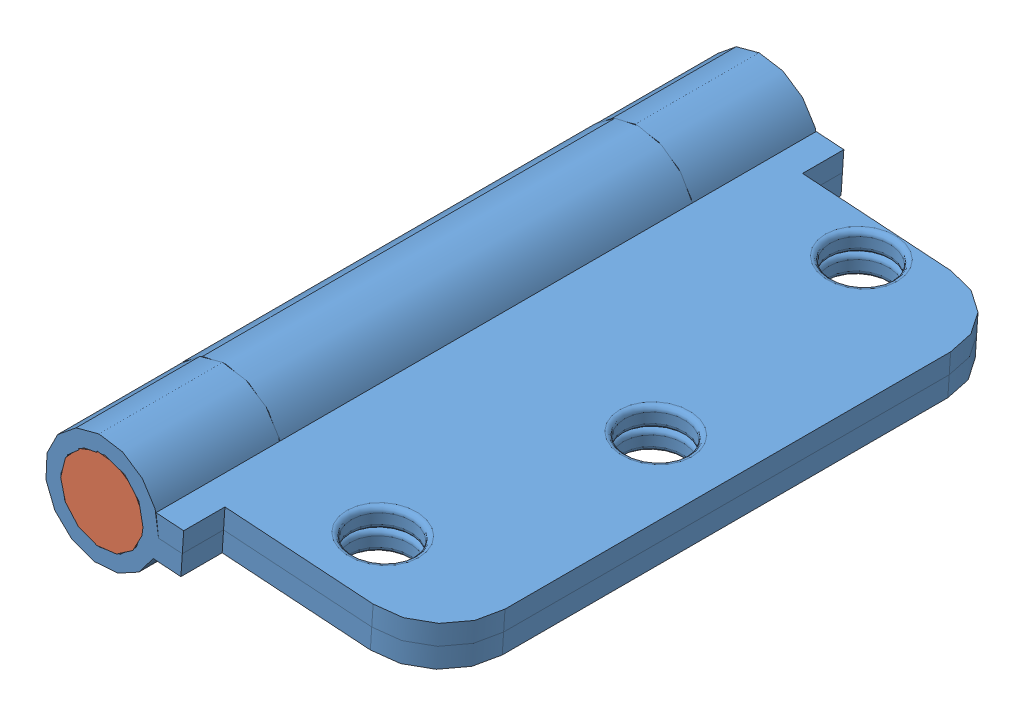
SolidWorks assembly 211-006 Hinge Asm, configuration Default. Lengths in mm.
Overall size (55.2 21.07 101.6).
3 component instances, 2 part files, 5 mates.
Components (placement in the parent):
- 211-004 hinge-1: 211-004 hinge [2] at (19.5932 62.3826 76.5203) x (0.99773 -0.067347 0) z (0 0 1) size (54.15 17.46 101.6)
- 211-005 pin for hinge-1: 211-005 pin for hinge [Default] at (7.6382 63.1896 25.7203) size (12.7 12.7 101.6)
- 211-004 hinge-2: 211-004 hinge [1] at (19.792 59.187 76.5203) x (0.99773 -0.067347 0) z (0 0 1) size (54.15 17.46 101.6)
Mates (geometry in assembly coordinates):
- Concentric1: concentric: cylinder of 211-004 hinge-1 through (7.6382 63.1896 127.3203) axis (0 0 -1) radius 6.35; cylinder of 211-005 pin for hinge-1 through (7.6382 63.1896 127.3203) axis (0 0 -1) radius 6.35
- Concentric2: concentric: cylinder of 211-005 pin for hinge-1 through (7.6382 63.1896 127.3203) axis (0 0 -1) radius 6.35; cylinder of 211-004 hinge-2 through (7.6382 63.1896 127.3203) axis (0 0 -1) radius 6.35
- Coincident1: coincident: plane of 211-005 pin for hinge-1 through (7.6382 63.1896 127.3203) normal (0 0 1); plane of 211-004 hinge-2 through (19.792 59.187 127.3203) normal (0 0 1)
- Coincident2: coincident: plane of 211-004 hinge-1 through (7.6382 63.1896 44.7703) normal (0 0 -1); plane of 211-004 hinge-2 through (42.8139 60.8152 44.7703) normal (0 0 1)
- LimitAngle1: limit planar angle = 0 rad: plane of 211-004 hinge-2 through (42.8139 60.8152 110.8103) normal (0.067347 0.99773 0); plane of 211-004 hinge-1 through (42.8139 60.8152 110.8103) normal (-0.067347 -0.99773 0)
